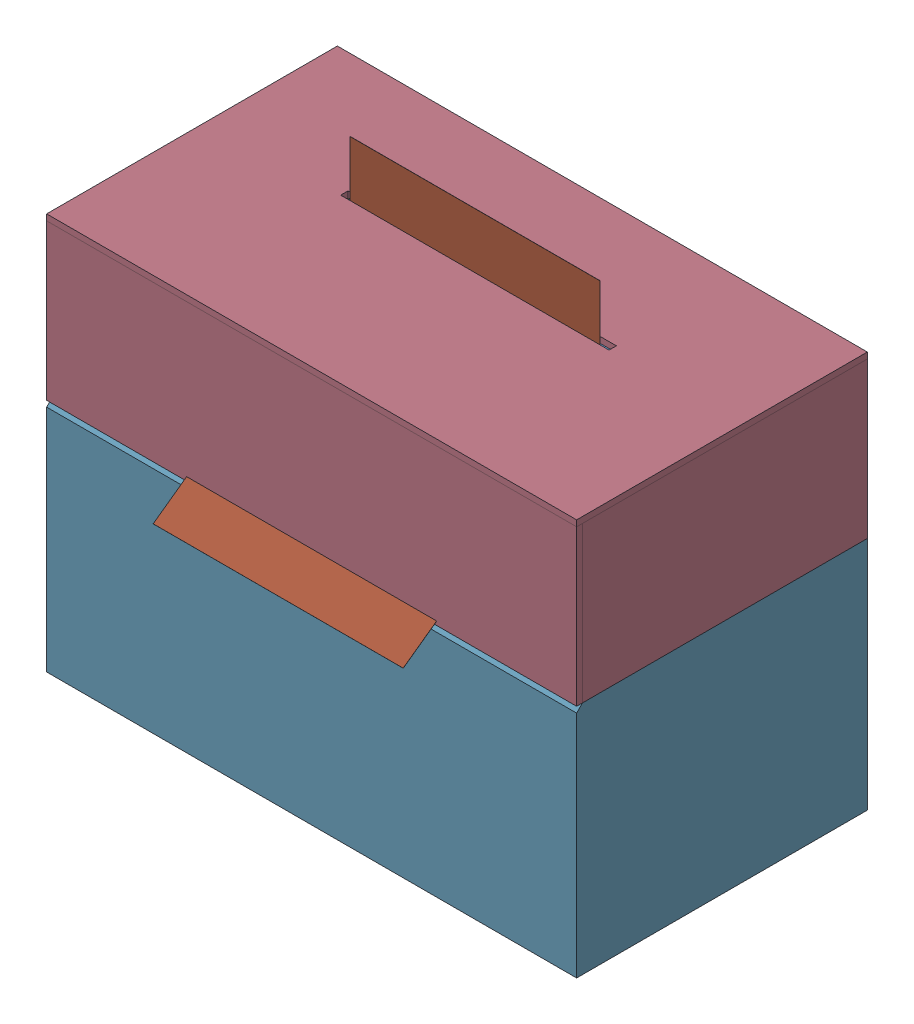
SolidWorks assembly Diverter Mk2, configuration Default. Lengths in mm.
Overall size (457.71 390.53 279.97).
41 component instances, 18 part files, 40 mates.
Components (placement in the parent):
- Scanner Shell-1: Scanner Shell [Default] at origin size (454.03 128.91 247.65) (hidden)
- Back Guide-1: Back Guide [Default] at (0 123.063 -38.1) size (236.86 120.65 26.99)
- Drive Guide Shell-1: Drive Guide Shell [Default] at (0 123.063 -15.875) x (-1 0 0) z (0 0 -1) size (274.64 123.06 138.26)
- Bottom Guide Shell-1: Bottom Guide Shell [Default] at (0 2.413 -15.875) x (-1 0 0) z (0 0 -1) size (234.37 87.28 124.27)
- Drive Assy-1: Drive Assy [Default] at (0 104.013 -3.81) x (1 0 0) z (0 0.932007 0.362439) size (238.76 28.57 28.57)
  - Drive Shaft-1: Drive Shaft [Default] at origin size (238.76 2.6 3)
  - Drive Wheel-1: Drive Wheel [Default] at (-14.605 0 0) size (25.4 28.57 28.57)
  - Drive Wheel-2: Drive Wheel [Default] at (-43.815 0 0) size (25.4 28.57 28.57)
  - Drive Wheel-3: Drive Wheel [Default] at (-73.025 0 0) size (25.4 28.57 28.57)
  - Drive Wheel-4: Drive Wheel [Default] at (-102.235 0 0) size (25.4 28.57 28.57)
  - Drive Wheel-5: Drive Wheel [Default] at (14.605 0 0) size (25.4 28.57 28.57)
  - Drive Wheel-6: Drive Wheel [Default] at (43.815 0 0) size (25.4 28.57 28.57)
  - Drive Wheel-7: Drive Wheel [Default] at (73.025 0 0) size (25.4 28.57 28.57)
  - Drive Wheel-8: Drive Wheel [Default] at (102.235 0 0) size (25.4 28.57 28.57)
- Idler Assy-1: Idler Assy [Default] at (0 104.013 -27.5896) x (1 0 0) z (0 -0.459753 0.888047) size (241.3 19.56 19.56)
  - Idler Shaft-1: Idler Shaft [Default] at origin size (241.3 5 5)
  - Idler-1: Idler [Default] at origin size (13.21 19.56 19.56)
  - Idler-2: Idler [Default] at (-29.21 0 0) size (13.21 19.56 19.56)
  - Idler-3: Idler [Default] at (-58.42 0 0) size (13.21 19.56 19.56)
  - Idler-4: Idler [Default] at (-87.63 0 0) size (13.21 19.56 19.56)
  - Idler-6: Idler [Default] at (29.21 0 0) x (-1 0 0) z (0 0 -1) size (13.21 19.56 19.56)
  - Idler-7: Idler [Default] at (58.42 0 0) x (-1 0 0) z (0 0 -1) size (13.21 19.56 19.56)
  - Idler-8: Idler [Default] at (87.63 0 0) x (-1 0 0) z (0 0 -1) size (13.21 19.56 19.56)
- Diverter Mechanism-1: Diverter Mechanism [Default] at (0 74.0975 -7.6132) x (-1 0 0) z (0 0.576773 -0.816905) size (196.85 43.8 48.01)
  - Diverter Tab-1: Diverter Tab [Default] at (0 0.127 -1.4566) x (1 0 0) z (0 -0.811308 0.58462) size (3.05 42.17 23.6)
  - Diverter Tab-2: Diverter Tab [Default] at (-29.21 0.127 -1.4566) x (1 0 0) z (0 -0.811308 0.58462) size (3.05 42.17 23.6)
  - Diverter Tab-3: Diverter Tab [Default] at (-58.42 0.127 -1.4566) x (1 0 0) z (0 -0.811308 0.58462) size (3.05 42.17 23.6)
  - Diverter Tab-4: Diverter Tab [Default] at (-87.63 0.127 -1.4566) x (1 0 0) z (0 -0.811308 0.58462) size (3.05 42.17 23.6)
  - Diverter Tab-5: Diverter Tab [Default] at (29.21 0.127 -1.4566) x (1 0 0) z (0 -0.811308 0.58462) size (3.05 42.17 23.6)
  - Diverter Tab-6: Diverter Tab [Default] at (58.42 0.127 -1.4566) x (1 0 0) z (0 -0.811308 0.58462) size (3.05 42.17 23.6)
  - Diverter Tab-7: Diverter Tab [Default] at (87.63 0.127 -1.4566) x (1 0 0) z (0 -0.811308 0.58462) size (3.05 42.17 23.6)
  - DiverterTabSpine-1: DiverterTabSpine [Default] at (0 0.127 -4.6316) size (196.85 3.05 12.7)
- DiverterServo-1: DiverterServo [Default] at (-129.0275 74.0975 2.8018) x (0 0 1) z (0 1 0) size (55.95 46.18 20.5)
- Paper-1: Paper [Default] at (0 98.6818 60.9936) x (-1 0 0) z (0 0 -1) size (215.9 204.89 169.99)
- Top Plate-1: Top Plate [Default] at (0 123.063 -30.2358) size (446.15 8.13 239.78) (hidden)
- FrontInnerFace-1: FrontInnerFace [Default] at (0 123.063 115.824) size (446.15 124.71 4.06) (hidden)
- BackInnerFace-1: BackInnerFace [Default] at (0 123.063 -115.824) x (-1 0 0) z (0 0 -1) size (446.15 124.71 4.06)
- SideInnerFace-1: SideInnerFace [Default] at (-223.0755 123.063 9.9265) x (0 0 -1) z (1 0 0) size (239.78 120.65 4.06) (hidden)
- SideInnerFace-2: SideInnerFace [Default] at (219.0115 123.063 9.9265) x (0 0 -1) z (1 0 0) size (239.78 120.65 4.06) (hidden)
- Top Outer Shell-1: Top Outer Shell [Default] at (0 127.127 -0.4445) size (457.71 139.45 251.08)
- Ballot Box-1: Ballot Box [Default] at (0 -210.312 -0.4445) size (457.71 212.72 251.08)
Mates (geometry in assembly coordinates):
- Coincident1: coincident anti-aligned: plane of Scanner Shell-1 through (0 123.063 0) normal (0 -1 0); plane of Back Guide-1 through (115.8875 123.063 -38.1) normal (0 1 0)
- Coincident2: coincident aligned: plane of Back Guide-1 through (0 123.063 -38.1) normal (1 0 0); plane of assembly through (0 0 0) normal (1 0 0)
- Coincident3: coincident aligned: plane of Back Guide-1 through (115.8875 123.063 -22.225) normal (0 0 1); plane of Scanner Shell-1 through (-115.8875 0 -22.225) normal (0 0 1)
- Coincident4: coincident aligned: plane of Scanner Shell-1 through (-115.8875 0 -15.875) normal (0 0 -1); plane of Drive Guide Shell-1 through (-118.4275 123.063 -15.875) normal (0 0 -1)
- Coincident5: coincident anti-aligned: plane of Drive Guide Shell-1 through (0 123.063 -15.875) normal (-1 0 0); plane of assembly through (0 0 0) normal (1 0 0)
- Coincident6: coincident anti-aligned: plane of Scanner Shell-1 through (0 123.063 0) normal (0 -1 0); plane of Drive Guide Shell-1 through (-118.4275 123.063 15.875) normal (0 1 0)
- Coincident7: coincident aligned: plane of Scanner Shell-1 through (-115.8875 0 -15.875) normal (0 0 -1); plane of Bottom Guide Shell-1 through (-115.8875 2.413 -15.875) normal (0 0 -1)
- Coincident8: coincident anti-aligned: plane of Bottom Guide Shell-1 through (0 2.413 -15.875) normal (-1 0 0); plane of assembly through (0 0 0) normal (1 0 0)
- Coincident9: coincident aligned: plane of Back Guide-1 through (115.8875 2.413 -38.1) normal (0 -1 0); plane of Bottom Guide Shell-1 through (-115.8875 2.413 108.3936) normal (0 -1 0)
- Coincident10: coincident aligned: plane of Drive Assy-1/Drive Shaft-1; plane of assembly through (0 0 0) normal (1 0 0)
- Coincident11: coincident aligned: plane of ?; plane of assembly through (0 0 0) normal (1 0 0)
- Distance1: distance = 19.05 mm: line of Idler Assy-1/Idler Shaft-1 through (-132.715 104.013 -27.5896) axis (1 0 0); plane of Scanner Shell-1 through (0 123.063 0) normal (0 -1 0)
- Distance2: distance = 19.05 mm: line of Drive Assy-1/Drive Shaft-1 through (-131.318 104.013 -3.81) axis (1 0 0); plane of Scanner Shell-1 through (0 123.063 0) normal (0 -1 0)
- Distance3: distance = 12.065 mm: line of Drive Assy-1/Drive Shaft-1 through (-131.318 104.013 -3.81) axis (1 0 0); plane of Drive Guide Shell-1 through (-118.4275 123.063 -15.875) normal (0 0 -1)
- Coincident18: coincident anti-aligned: plane of Diverter Mechanism-1/Diverter Tab-1; plane of assembly through (0 0 0) normal (1 0 0)
- LimitAngle4: limit planar angle = 0.331613 rad aligned: plane of Diverter Mechanism-1/Diverter Tab-1 through (-1.524 97.8722 -24.8637) normal (0 -0.325568 -0.945519); plane of Bottom Guide Shell-1 through (-115.8875 2.413 -15.875) normal (0 0 -1)
- Distance6: distance = 9.525 mm: line of Diverter Mechanism-1/Diverter Tab-1 through (1.7463 73.3611 -6.35) axis (-1 0 0); plane of Bottom Guide Shell-1 through (-115.8875 2.413 -15.875) normal (0 0 -1)
- Distance7: distance = 9.525 mm: line of Diverter Mechanism-1/Diverter Tab-1 through (1.7463 73.3611 -6.35) axis (-1 0 0); plane of Bottom Guide Shell-1 through (-115.8875 89.2465 -12.1016) normal (0 0.811288 0.584646)
- Coincident19: coincident anti-aligned: plane of Back Guide-1 through (-118.4275 99.2505 -31.75) normal (-1 0 0); plane of DiverterServo-1 through (-118.4275 81.9663 -15.817) normal (1 0 0)
- Coincident20: coincident anti-aligned: line of Diverter Mechanism-1 through (-108.2675 74.0975 -7.6132) axis (1 0 0); line of DiverterServo-1 through (-109.765 74.0975 -7.6132) axis (-1 0 0)
- Parallel1: parallel aligned: plane of Drive Guide Shell-1 through (-155.2575 92.513 -18.3745) normal (0 1 0); plane of DiverterServo-1 through (-157.9075 84.3475 -15.817) normal (0 1 0)
- Coincident21: coincident anti-aligned: plane of Paper-1 through (-107.95 180.213 -15.875) normal (0 0 1); plane of Drive Guide Shell-1 through (0 123.063 -15.875) normal (0 0 -1)
- Coincident22: coincident anti-aligned: plane of Paper-1 through (0 98.6818 60.9936) normal (-1 0 0); plane of assembly through (0 0 0) normal (1 0 0)
- Coincident23: coincident aligned: plane of Top Plate-1 through (0 123.063 -30.2358) normal (1 0 0); plane of assembly through (0 0 0) normal (1 0 0)
- Coincident24: coincident anti-aligned: plane of Drive Guide Shell-1 through (-118.4275 123.063 15.875) normal (0 1 0); plane of Top Plate-1 through (0 123.063 -30.2358) normal (0 -1 0)
- Coincident25: coincident aligned: plane of Back Guide-1 through (115.8875 123.063 -22.225) normal (0 0 1); plane of Top Plate-1 through (-115.8875 127.127 -22.225) normal (0 0 1)
- Coincident26: coincident aligned: plane of FrontInnerFace-1 through (0 123.063 115.824) normal (1 0 0); plane of assembly through (0 0 0) normal (1 0 0)
- Coincident27: coincident anti-aligned: plane of Top Plate-1 through (-197.6755 127.127 115.824) normal (0 0 1); plane of FrontInnerFace-1 through (0 123.063 115.824) normal (0 0 -1)
- Coincident28: coincident anti-aligned: plane of Top Plate-1 through (0 123.063 -30.2358) normal (0 -1 0); plane of FrontInnerFace-1 through (-178.6255 123.063 119.888) normal (0 1 0)
- Coincident29: coincident anti-aligned: plane of BackInnerFace-1 through (0 123.063 -115.824) normal (-1 0 0); plane of assembly through (0 0 0) normal (1 0 0)
- Coincident30: coincident anti-aligned: plane of Top Plate-1 through (0 123.063 -30.2358) normal (0 -1 0); plane of BackInnerFace-1 through (223.0755 123.063 -119.888) normal (0 1 0)
- Coincident31: coincident aligned: plane of Top Plate-1 through (-223.0755 127.127 -119.888) normal (0 0 -1); plane of BackInnerFace-1 through (0 123.063 -119.888) normal (0 0 -1)
- Coincident32: coincident aligned: plane of Top Plate-1 through (-223.0755 127.127 119.888) normal (-1 0 0); plane of SideInnerFace-1 through (-223.0755 123.063 9.9265) normal (-1 0 0)
- Coincident33: coincident anti-aligned: plane of Top Plate-1 through (0 123.063 -30.2358) normal (0 -1 0); plane of SideInnerFace-1 through (-219.0115 123.063 -115.824) normal (0 1 0)
- Coincident34: coincident anti-aligned: plane of FrontInnerFace-1 through (0 123.063 119.888) normal (0 0 1); plane of Top Outer Shell-1 through (0 127.127 119.888) normal (0 0 -1)
- Coincident35: coincident aligned: plane of Top Outer Shell-1 through (0 127.127 -0.4445) normal (1 0 0); plane of assembly through (0 0 0) normal (1 0 0)
- Coincident36: coincident anti-aligned: plane of Top Plate-1 through (0 127.127 -30.2358) normal (0 1 0); plane of Top Outer Shell-1 through (0 127.127 -0.4445) normal (0 -1 0)
- Coincident37: coincident aligned: plane of Ballot Box-1 through (0 -210.312 -0.4445) normal (1 0 0); plane of assembly through (0 0 0) normal (1 0 0)
- Coincident38: coincident aligned: plane of Top Outer Shell-1 through (0 127.127 125.095) normal (0 0 1); plane of Ballot Box-1 through (-228.854 -7.112 125.095) normal (0 0 1)
- Coincident39: coincident anti-aligned: plane of Top Outer Shell-1 through (-223.647 -7.112 119.888) normal (0 -1 0); plane of Ballot Box-1 through (0 -7.112 -0.4445) normal (0 1 0)
